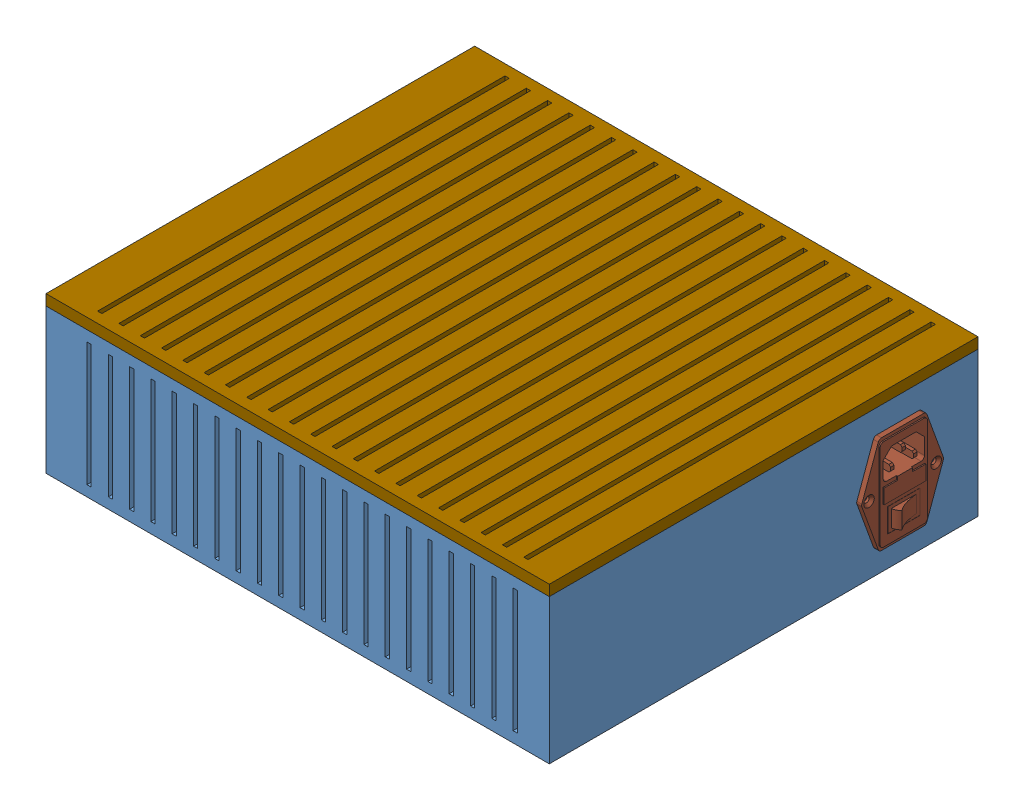
SolidWorks assembly control_box_ssy, configuration Default. Lengths in mm.
Overall size (358.32 92.75 255.52).
319 component instances, 47 part files, 18 mates.
Components (placement in the parent):
- control_box-1: control_box [Default] at (146.6562 115.1986 240.0764) size (300 86.35 255.52)
- PSU-1: PSU [Default] at (123.0062 115.1986 301.4884) x (0 0 -1) z (1 0 0) size (120 65 240)
- Duex5-1: Duex5 [Default] at (64.5062 115.1986 168.6644) size (119.17 14.96 75.22)
  - Duet WiFi v1-1: Duet WiFi v1 [Default] at origin (suppressed, hidden)
  - 2 pole terminal block v7-1: 2 pole terminal block v7 [Default] at (58.1029 1.6572 -18.2256) x (0 0 -1) z (1 0 0) size (7.2 9 6)
  - 2 pole terminal block v7-2: 2 pole terminal block v7 [Default] at (58.1029 1.6572 -10.5256) x (0 0 -1) z (1 0 0) size (7.2 9 6)
  - Molex PCB 4 pin v3_1-1: Molex PCB 4 pin v3_1 [Default] at (18.0541 13.1477 49.9775) x (1 0 0) z (0 1 0) size (10.16 5.79 14.92)
    - BASE9710016-1: BASE9710016 [Default] at (2.54 2.895 -8.22) size (10.16 5.79 11.5)
    - PINO9710016-1: PINO9710016 [Default] at (1.27 3.325 -0.72) size (0.65 0.65 14.2)
    - PINO9710016-2: PINO9710016 [Default] at (3.81 3.325 -0.72) size (0.65 0.65 14.2)
    - PINO9710016-3: PINO9710016 [Default] at (6.35 3.325 -0.72) size (0.65 0.65 14.2)
    - PINO9710016-4: PINO9710016 [Default] at (8.89 3.325 -0.72) size (0.65 0.65 14.2)
  - Molex PCB 4 pin v3_2-1: Molex PCB 4 pin v3_2 [Default] at (-4.9459 13.1477 49.9775) x (1 0 0) z (0 1 0) size (10.16 5.79 14.92)
    - BASE9710016-1: BASE9710016 [Default] at (2.54 2.895 -8.22) size (10.16 5.79 11.5)
    - PINO9710016-1: PINO9710016 [Default] at (1.27 3.325 -0.72) size (0.65 0.65 14.2)
    - PINO9710016-2: PINO9710016 [Default] at (3.81 3.325 -0.72) size (0.65 0.65 14.2)
    - PINO9710016-3: PINO9710016 [Default] at (6.35 3.325 -0.72) size (0.65 0.65 14.2)
    - PINO9710016-4: PINO9710016 [Default] at (8.89 3.325 -0.72) size (0.65 0.65 14.2)
  - Molex PCB 4 pin v3_3-1: Molex PCB 4 pin v3_3 [Default] at (-27.9459 13.1477 49.9775) x (1 0 0) z (0 1 0) size (10.16 5.79 14.92)
    - BASE9710016-1: BASE9710016 [Default] at (2.54 2.895 -8.22) size (10.16 5.79 11.5)
    - PINO9710016-1: PINO9710016 [Default] at (1.27 3.325 -0.72) size (0.65 0.65 14.2)
    - PINO9710016-2: PINO9710016 [Default] at (3.81 3.325 -0.72) size (0.65 0.65 14.2)
    - PINO9710016-3: PINO9710016 [Default] at (6.35 3.325 -0.72) size (0.65 0.65 14.2)
    - PINO9710016-4: PINO9710016 [Default] at (8.89 3.325 -0.72) size (0.65 0.65 14.2)
  - Molex PCB 4 pin v3_4-1: Molex PCB 4 pin v3_4 [Default] at (-50.9459 13.1477 49.9775) x (1 0 0) z (0 1 0) size (10.16 5.79 14.92)
    - BASE9710016-1: BASE9710016 [Default] at (2.54 2.895 -8.22) size (10.16 5.79 11.5)
    - PINO9710016-1: PINO9710016 [Default] at (1.27 3.325 -0.72) size (0.65 0.65 14.2)
    - PINO9710016-2: PINO9710016 [Default] at (3.81 3.325 -0.72) size (0.65 0.65 14.2)
    - PINO9710016-3: PINO9710016 [Default] at (6.35 3.325 -0.72) size (0.65 0.65 14.2)
    - PINO9710016-4: PINO9710016 [Default] at (8.89 3.325 -0.72) size (0.65 0.65 14.2)
  - 2 pole terminal block v7-3: 2 pole terminal block v7 [Default] at (58.1029 1.6572 -2.8256) x (0 0 -1) z (1 0 0) size (7.2 9 6)
  - Trinamic 2660-PA v3_4-1: Trinamic 2660-PA v3_4 [Default] at (-45.9607 1.6002 32.1353) x (-1 0 -0.000001) z (0.000001 0 -1) size (12 1.6 12)
    - Component1 (5)-1: Component1 (5) [Default] at origin size (12 1.6 12)
  - PCB 7mm cap v8_1-1: PCB 7mm cap v8_1 [Default] at (21.8776 1.5787 20.4495) size (7 8 8.14)
    - Component1_3-1: Component1_3 [Default] at origin size (7 8 8.14)
  - PCB 7mm cap v8_2-1: PCB 7mm cap v8_2 [Default] at (-1.1224 1.5787 20.4495) size (7 8 8.14)
    - Component1_3-1: Component1_3 [Default] at origin size (7 8 8.14)
  - PCB 7mm cap v8_3-1: PCB 7mm cap v8_3 [Default] at (-25.1224 1.5787 20.4495) size (7 8 8.14)
    - Component1_3-1: Component1_3 [Default] at origin size (7 8 8.14)
  - PCB 7mm cap v8_4-1: PCB 7mm cap v8_4 [Default] at (-48.1224 1.5787 20.4495) size (7 8 8.14)
    - Component1_3-1: Component1_3 [Default] at origin size (7 8 8.14)
  - Molex PCB 2 pin v2 (6)_1-1: Molex PCB 2 pin v2 (6)_1 [Default] at (-44.2809 13.1082 -19.4574) x (1 0 0) z (0 1 0) size (10.16 5.79 14.92)
    - BASE9710016-1: BASE9710016 [Default] at (2.54 2.895 -8.22) size (10.16 5.79 11.5)
    - PINO9710016-1: PINO9710016 [Default] at (1.27 3.325 -0.72) size (0.65 0.65 14.2)
    - PINO9710016-2: PINO9710016 [Default] at (3.81 3.325 -0.72) size (0.65 0.65 14.2)
  - Molex PCB 2 pin v2 (6)_2-1: Molex PCB 2 pin v2 (6)_2 [Default] at (-37.2809 13.1082 -19.4574) x (1 0 0) z (0 1 0) size (10.16 5.79 14.92)
    - BASE9710016-1: BASE9710016 [Default] at (2.54 2.895 -8.22) size (10.16 5.79 11.5)
    - PINO9710016-1: PINO9710016 [Default] at (1.27 3.325 -0.72) size (0.65 0.65 14.2)
    - PINO9710016-2: PINO9710016 [Default] at (3.81 3.325 -0.72) size (0.65 0.65 14.2)
  - Molex PCB 2 pin v2 (6)_3-1: Molex PCB 2 pin v2 (6)_3 [Default] at (-30.2809 13.1082 -19.4574) x (1 0 0) z (0 1 0) size (10.16 5.79 14.92)
    - BASE9710016-1: BASE9710016 [Default] at (2.54 2.895 -8.22) size (10.16 5.79 11.5)
    - PINO9710016-1: PINO9710016 [Default] at (1.27 3.325 -0.72) size (0.65 0.65 14.2)
    - PINO9710016-2: PINO9710016 [Default] at (3.81 3.325 -0.72) size (0.65 0.65 14.2)
  - Molex PCB 3 pin v2 v6_1-1: Molex PCB 3 pin v2 v6_1 [Default] at (-22.2009 13.1082 -19.4574) x (1 0 0) z (0 1 0) size (7.62 5.79 14.92)
    - BASE9710016_2-1: BASE9710016_2 [Default] at (2.54 2.895 -8.22) size (7.62 5.79 11.5)
    - PINO9710016_2-1: PINO9710016_2 [Default] at (1.27 3.325 -0.72) size (0.65 0.65 14.2)
    - PINO9710016_2-2: PINO9710016_2 [Default] at (3.81 3.325 -0.72) size (0.65 0.65 14.2)
    - PINO9710016_2-3: PINO9710016_2 [Default] at (6.35 3.325 -0.72) size (0.65 0.65 14.2)
  - Molex PCB 3 pin v2 v6_2-1: Molex PCB 3 pin v2 v6_2 [Default] at (-12.2009 13.1082 -19.4574) x (1 0 0) z (0 1 0) size (7.62 5.79 14.92)
    - BASE9710016_2-1: BASE9710016_2 [Default] at (2.54 2.895 -8.22) size (7.62 5.79 11.5)
    - PINO9710016_2-1: PINO9710016_2 [Default] at (1.27 3.325 -0.72) size (0.65 0.65 14.2)
    - PINO9710016_2-2: PINO9710016_2 [Default] at (3.81 3.325 -0.72) size (0.65 0.65 14.2)
    - PINO9710016_2-3: PINO9710016_2 [Default] at (6.35 3.325 -0.72) size (0.65 0.65 14.2)
  - Molex PCB 3 pin v2 v6_3-1: Molex PCB 3 pin v2 v6_3 [Default] at (-2.2009 13.1082 -19.4574) x (1 0 0) z (0 1 0) size (7.62 5.79 14.92)
    - BASE9710016_2-1: BASE9710016_2 [Default] at (2.54 2.895 -8.22) size (7.62 5.79 11.5)
    - PINO9710016_2-1: PINO9710016_2 [Default] at (1.27 3.325 -0.72) size (0.65 0.65 14.2)
    - PINO9710016_2-2: PINO9710016_2 [Default] at (3.81 3.325 -0.72) size (0.65 0.65 14.2)
    - PINO9710016_2-3: PINO9710016_2 [Default] at (6.35 3.325 -0.72) size (0.65 0.65 14.2)
  - Molex PCB 3 pin v2 v6_4-1: Molex PCB 3 pin v2 v6_4 [Default] at (7.7991 13.1082 -19.4574) x (1 0 0) z (0 1 0) size (7.62 5.79 14.92)
    - BASE9710016_2-1: BASE9710016_2 [Default] at (2.54 2.895 -8.22) size (7.62 5.79 11.5)
    - PINO9710016_2-1: PINO9710016_2 [Default] at (1.27 3.325 -0.72) size (0.65 0.65 14.2)
    - PINO9710016_2-2: PINO9710016_2 [Default] at (3.81 3.325 -0.72) size (0.65 0.65 14.2)
    - PINO9710016_2-3: PINO9710016_2 [Default] at (6.35 3.325 -0.72) size (0.65 0.65 14.2)
  - Molex PCB 3 pin v2 v6_5-1: Molex PCB 3 pin v2 v6_5 [Default] at (17.7991 13.1082 -19.4574) x (1 0 0) z (0 1 0) size (7.62 5.79 14.92)
    - BASE9710016_2-1: BASE9710016_2 [Default] at (2.54 2.895 -8.22) size (7.62 5.79 11.5)
    - PINO9710016_2-1: PINO9710016_2 [Default] at (1.27 3.325 -0.72) size (0.65 0.65 14.2)
    - PINO9710016_2-2: PINO9710016_2 [Default] at (3.81 3.325 -0.72) size (0.65 0.65 14.2)
    - PINO9710016_2-3: PINO9710016_2 [Default] at (6.35 3.325 -0.72) size (0.65 0.65 14.2)
  - PCB 7mm cap v8_5-1: PCB 7mm cap v8_5 [Default] at (31.8776 1.5787 0.4495) size (7 8 8.14)
    - Component1_3-1: Component1_3 [Default] at origin size (7 8 8.14)
  - PCB 7mm cap v8_6-1: PCB 7mm cap v8_6 [Default] at (36.8776 1.5787 -19.5505) size (7 8 8.14)
    - Component1_3-1: Component1_3 [Default] at origin size (7 8 8.14)
  - MOSFET v9-1: MOSFET v9 [Default] at (44.8765 1.6199 -9.2021) x (0 0 1) z (-1 0 0) size (6.4 2.4 9.33)
  - MOSFET v9-2: MOSFET v9 [Default] at (23.8765 1.6199 -9.2021) x (0 0 1) z (-1 0 0) size (6.4 2.4 9.33)
  - MOSFET v9-3: MOSFET v9 [Default] at (23.8765 1.6199 9.7979) x (0 0 1) z (-1 0 0) size (6.4 2.4 9.33)
  - MOSFET v9-4: MOSFET v9 [Default] at (44.8765 1.6199 9.7979) x (0 0 1) z (-1 0 0) size (6.4 2.4 9.33)
  - PCB 7mm cap v8_7-1: PCB 7mm cap v8_7 [Default] at (-42.1224 1.5787 6.4495) size (7 8 8.14)
    - Component1_3-1: Component1_3 [Default] at origin size (7 8 8.14)
  - PCB 7mm cap v8_8-1: PCB 7mm cap v8_8 [Default] at (-54.5623 1.5787 -3.6684) size (7 8 8.14)
    - Component1_3-1: Component1_3 [Default] at origin size (7 8 8.14)
  - Micro P v5_1-1: Micro P v5_1 [Default] at (-11.5775 1.6187 -10.0194) x (-1 0 0) z (0 0 -1) size (5 1.2 5.8)
    - Component1 (2)-1: Component1 (2) [Default] at origin size (5 1.2 5.8)
  - Micro P v5_2-1: Micro P v5_2 [Default] at (-19.5775 1.6187 -5.0194) x (-1 0 0) z (0 0 -1) size (5 1.2 5.8)
    - Component1 (2)-1: Component1 (2) [Default] at origin size (5 1.2 5.8)
- Duet WIfi Rev 4-1: Duet WIfi Rev 4 [Default] at (193.5062 115.1986 168.6644) size (129 22.52 100)
  - Main PCB v56-1: Main PCB v56 [Default] at origin size (123 1.6 100)
  - Molex PCB 2 pin v2-1: Molex PCB 2 pin v2 [Default] at (-35.5344 13.1082 -6.1109) x (1 0 0) z (0 1 0) size (5.08 5.79 14.92)
    - BASE9710016_1-1: BASE9710016_1 [Default] at (2.54 2.895 -8.22) size (5.08 5.79 11.5)
    - PINO9710016_1-1: PINO9710016_1 [Default] at (1.27 3.325 -0.72) size (0.65 0.65 14.2)
    - PINO9710016_1-2: PINO9710016_1 [Default] at (3.81 3.325 -0.72) size (0.65 0.65 14.2)
  - Molex PCB 2 pin v2_1-1: Molex PCB 2 pin v2_1 [Default] at (-28.4802 13.1082 -6.1109) x (1 0 0) z (0 1 0) size (5.08 5.79 14.92)
    - BASE9710016_1-1: BASE9710016_1 [Default] at (2.54 2.895 -8.22) size (5.08 5.79 11.5)
    - PINO9710016_1-1: PINO9710016_1 [Default] at (1.27 3.325 -0.72) size (0.65 0.65 14.2)
    - PINO9710016_1-2: PINO9710016_1 [Default] at (3.81 3.325 -0.72) size (0.65 0.65 14.2)
  - microSD1 v4-1: microSD1 v4 [Default] at (-62.4462 1.5952 12.9853) x (0 0 1) z (-1 0 0) size (14.1 1.88 15.2)
  - Molex PCB 2 pin v2_2-1: Molex PCB 2 pin v2_2 [Default] at (13.9179 13.1082 2.5426) x (1 0 0) z (0 1 0) size (5.08 5.79 14.92)
    - BASE9710016_1-1: BASE9710016_1 [Default] at (2.54 2.895 -8.22) size (5.08 5.79 11.5)
    - PINO9710016_1-1: PINO9710016_1 [Default] at (1.27 3.325 -0.72) size (0.65 0.65 14.2)
    - PINO9710016_1-2: PINO9710016_1 [Default] at (3.81 3.325 -0.72) size (0.65 0.65 14.2)
  - Molex PCB 2 pin v2_3-1: Molex PCB 2 pin v2_3 [Default] at (20.2886 13.1082 2.5426) x (1 0 0) z (0 1 0) size (5.08 5.79 14.92)
    - BASE9710016_1-1: BASE9710016_1 [Default] at (2.54 2.895 -8.22) size (5.08 5.79 11.5)
    - PINO9710016_1-1: PINO9710016_1 [Default] at (1.27 3.325 -0.72) size (0.65 0.65 14.2)
    - PINO9710016_1-2: PINO9710016_1 [Default] at (3.81 3.325 -0.72) size (0.65 0.65 14.2)
  - Molex PCB 2 pin v2_4-1: Molex PCB 2 pin v2_4 [Default] at (26.5531 13.1082 2.5426) x (1 0 0) z (0 1 0) size (5.08 5.79 14.92)
    - BASE9710016_1-1: BASE9710016_1 [Default] at (2.54 2.895 -8.22) size (5.08 5.79 11.5)
    - PINO9710016_1-1: PINO9710016_1 [Default] at (1.27 3.325 -0.72) size (0.65 0.65 14.2)
    - PINO9710016_1-2: PINO9710016_1 [Default] at (3.81 3.325 -0.72) size (0.65 0.65 14.2)
  - Molex PCB 2 pin v2_5-1: Molex PCB 2 pin v2_5 [Default] at (33.1361 13.1082 2.5426) x (1 0 0) z (0 1 0) size (5.08 5.79 14.92)
    - BASE9710016_1-1: BASE9710016_1 [Default] at (2.54 2.895 -8.22) size (5.08 5.79 11.5)
    - PINO9710016_1-1: PINO9710016_1 [Default] at (1.27 3.325 -0.72) size (0.65 0.65 14.2)
    - PINO9710016_1-2: PINO9710016_1 [Default] at (3.81 3.325 -0.72) size (0.65 0.65 14.2)
  - Molex PCB 2 pin v2_6-1: Molex PCB 2 pin v2_6 [Default] at (39.7191 13.1082 2.5426) x (1 0 0) z (0 1 0) size (5.08 5.79 14.92)
    - BASE9710016_1-1: BASE9710016_1 [Default] at (2.54 2.895 -8.22) size (5.08 5.79 11.5)
    - PINO9710016_1-1: PINO9710016_1 [Default] at (1.27 3.325 -0.72) size (0.65 0.65 14.2)
    - PINO9710016_1-2: PINO9710016_1 [Default] at (3.81 3.325 -0.72) size (0.65 0.65 14.2)
  - Molex PCB 3 pin v2 v6-1: Molex PCB 3 pin v2 v6 [Default] at (-20.7566 13.2093 -6.0914) x (1 0 0) z (0 1 0) size (7.62 5.79 14.92)
    - BASE9710016_2-1: BASE9710016_2 [Default] at (2.54 2.895 -8.22) size (7.62 5.79 11.5)
    - PINO9710016_2-1: PINO9710016_2 [Default] at (1.27 3.325 -0.72) size (0.65 0.65 14.2)
    - PINO9710016_2-2: PINO9710016_2 [Default] at (3.81 3.325 -0.72) size (0.65 0.65 14.2)
    - PINO9710016_2-3: PINO9710016_2 [Default] at (6.35 3.325 -0.72) size (0.65 0.65 14.2)
  - Molex PCB 3 pin v2 v6_1-1: Molex PCB 3 pin v2 v6_1 [Default] at (-10.5889 13.2093 -6.0914) x (1 0 0) z (0 1 0) size (7.62 5.79 14.92)
    - BASE9710016_2-1: BASE9710016_2 [Default] at (2.54 2.895 -8.22) size (7.62 5.79 11.5)
    - PINO9710016_2-1: PINO9710016_2 [Default] at (1.27 3.325 -0.72) size (0.65 0.65 14.2)
    - PINO9710016_2-2: PINO9710016_2 [Default] at (3.81 3.325 -0.72) size (0.65 0.65 14.2)
    - PINO9710016_2-3: PINO9710016_2 [Default] at (6.35 3.325 -0.72) size (0.65 0.65 14.2)
  - Molex PCB 3 pin v2 v6_2-1: Molex PCB 3 pin v2 v6_2 [Default] at (-1.0164 13.2093 -6.0914) x (1 0 0) z (0 1 0) size (7.62 5.79 14.92)
    - BASE9710016_2-1: BASE9710016_2 [Default] at (2.54 2.895 -8.22) size (7.62 5.79 11.5)
    - PINO9710016_2-1: PINO9710016_2 [Default] at (1.27 3.325 -0.72) size (0.65 0.65 14.2)
    - PINO9710016_2-2: PINO9710016_2 [Default] at (3.81 3.325 -0.72) size (0.65 0.65 14.2)
    - PINO9710016_2-3: PINO9710016_2 [Default] at (6.35 3.325 -0.72) size (0.65 0.65 14.2)
  - Molex PCB 3 pin v2 v6_3-1: Molex PCB 3 pin v2 v6_3 [Default] at (9.3326 13.2093 -6.0914) x (1 0 0) z (0 1 0) size (7.62 5.79 14.92)
    - BASE9710016_2-1: BASE9710016_2 [Default] at (2.54 2.895 -8.22) size (7.62 5.79 11.5)
    - PINO9710016_2-1: PINO9710016_2 [Default] at (1.27 3.325 -0.72) size (0.65 0.65 14.2)
    - PINO9710016_2-2: PINO9710016_2 [Default] at (3.81 3.325 -0.72) size (0.65 0.65 14.2)
    - PINO9710016_2-3: PINO9710016_2 [Default] at (6.35 3.325 -0.72) size (0.65 0.65 14.2)
  - Molex PCB 3 pin v2 v6_4-1: Molex PCB 3 pin v2 v6_4 [Default] at (19.2437 13.2093 -6.0914) x (1 0 0) z (0 1 0) size (7.62 5.79 14.92)
    - BASE9710016_2-1: BASE9710016_2 [Default] at (2.54 2.895 -8.22) size (7.62 5.79 11.5)
    - PINO9710016_2-1: PINO9710016_2 [Default] at (1.27 3.325 -0.72) size (0.65 0.65 14.2)
    - PINO9710016_2-2: PINO9710016_2 [Default] at (3.81 3.325 -0.72) size (0.65 0.65 14.2)
    - PINO9710016_2-3: PINO9710016_2 [Default] at (6.35 3.325 -0.72) size (0.65 0.65 14.2)
  - Molex PCB 4 pin v3-1: Molex PCB 4 pin v3 [Default] at (-37.9459 13.1477 49.9775) x (1 0 0) z (0 1 0) size (10.16 5.79 14.92)
    - BASE9710016-1: BASE9710016 [Default] at (2.54 2.895 -8.22) size (10.16 5.79 11.5)
    - PINO9710016-1: PINO9710016 [Default] at (1.27 3.325 -0.72) size (0.65 0.65 14.2)
    - PINO9710016-2: PINO9710016 [Default] at (3.81 3.325 -0.72) size (0.65 0.65 14.2)
    - PINO9710016-3: PINO9710016 [Default] at (6.35 3.325 -0.72) size (0.65 0.65 14.2)
    - PINO9710016-4: PINO9710016 [Default] at (8.89 3.325 -0.72) size (0.65 0.65 14.2)
  - Molex PCB 4 pin v3_1-1: Molex PCB 4 pin v3_1 [Default] at (-26.9715 13.1477 49.9775) x (1 0 0) z (0 1 0) size (10.16 5.79 14.92)
    - BASE9710016-1: BASE9710016 [Default] at (2.54 2.895 -8.22) size (10.16 5.79 11.5)
    - PINO9710016-1: PINO9710016 [Default] at (1.27 3.325 -0.72) size (0.65 0.65 14.2)
    - PINO9710016-2: PINO9710016 [Default] at (3.81 3.325 -0.72) size (0.65 0.65 14.2)
    - PINO9710016-3: PINO9710016 [Default] at (6.35 3.325 -0.72) size (0.65 0.65 14.2)
    - PINO9710016-4: PINO9710016 [Default] at (8.89 3.325 -0.72) size (0.65 0.65 14.2)
  - Molex PCB 4 pin v3_2-1: Molex PCB 4 pin v3_2 [Default] at (-13.0474 13.1477 -49.9787) x (-1 0 0) z (0 1 0) size (10.16 5.79 14.92)
    - BASE9710016-1: BASE9710016 [Default] at (2.54 2.895 -8.22) size (10.16 5.79 11.5)
    - PINO9710016-1: PINO9710016 [Default] at (1.27 3.325 -0.72) size (0.65 0.65 14.2)
    - PINO9710016-2: PINO9710016 [Default] at (3.81 3.325 -0.72) size (0.65 0.65 14.2)
    - PINO9710016-3: PINO9710016 [Default] at (6.35 3.325 -0.72) size (0.65 0.65 14.2)
    - PINO9710016-4: PINO9710016 [Default] at (8.89 3.325 -0.72) size (0.65 0.65 14.2)
  - Molex PCB 4 pin v3_3-1: Molex PCB 4 pin v3_3 [Default] at (3.87 13.1477 -49.9787) x (-1 0 0) z (0 1 0) size (10.16 5.79 14.92)
    - BASE9710016-1: BASE9710016 [Default] at (2.54 2.895 -8.22) size (10.16 5.79 11.5)
    - PINO9710016-1: PINO9710016 [Default] at (1.27 3.325 -0.72) size (0.65 0.65 14.2)
    - PINO9710016-2: PINO9710016 [Default] at (3.81 3.325 -0.72) size (0.65 0.65 14.2)
    - PINO9710016-3: PINO9710016 [Default] at (6.35 3.325 -0.72) size (0.65 0.65 14.2)
    - PINO9710016-4: PINO9710016 [Default] at (8.89 3.325 -0.72) size (0.65 0.65 14.2)
  - Molex PCB 4 pin v3_4-1: Molex PCB 4 pin v3_4 [Default] at (20.2963 13.1477 -49.9787) x (-1 0 0) z (0 1 0) size (10.16 5.79 14.92)
    - BASE9710016-1: BASE9710016 [Default] at (2.54 2.895 -8.22) size (10.16 5.79 11.5)
    - PINO9710016-1: PINO9710016 [Default] at (1.27 3.325 -0.72) size (0.65 0.65 14.2)
    - PINO9710016-2: PINO9710016 [Default] at (3.81 3.325 -0.72) size (0.65 0.65 14.2)
    - PINO9710016-3: PINO9710016 [Default] at (6.35 3.325 -0.72) size (0.65 0.65 14.2)
    - PINO9710016-4: PINO9710016 [Default] at (8.89 3.325 -0.72) size (0.65 0.65 14.2)
  - Molex PCB 4 pin v3_5-1: Molex PCB 4 pin v3_5 [Default] at (36.6134 13.1477 -49.9787) x (-1 0 0) z (0 1 0) size (10.16 5.79 14.92)
    - BASE9710016-1: BASE9710016 [Default] at (2.54 2.895 -8.22) size (10.16 5.79 11.5)
    - PINO9710016-1: PINO9710016 [Default] at (1.27 3.325 -0.72) size (0.65 0.65 14.2)
    - PINO9710016-2: PINO9710016 [Default] at (3.81 3.325 -0.72) size (0.65 0.65 14.2)
    - PINO9710016-3: PINO9710016 [Default] at (6.35 3.325 -0.72) size (0.65 0.65 14.2)
    - PINO9710016-4: PINO9710016 [Default] at (8.89 3.325 -0.72) size (0.65 0.65 14.2)
  - Molex PCB 4 pin v3_6-1: Molex PCB 4 pin v3_6 [Default] at (53.5582 13.1477 -49.9787) x (-1 0 0) z (0 1 0) size (10.16 5.79 14.92)
    - BASE9710016-1: BASE9710016 [Default] at (2.54 2.895 -8.22) size (10.16 5.79 11.5)
    - PINO9710016-1: PINO9710016 [Default] at (1.27 3.325 -0.72) size (0.65 0.65 14.2)
    - PINO9710016-2: PINO9710016 [Default] at (3.81 3.325 -0.72) size (0.65 0.65 14.2)
    - PINO9710016-3: PINO9710016 [Default] at (6.35 3.325 -0.72) size (0.65 0.65 14.2)
    - PINO9710016-4: PINO9710016 [Default] at (8.89 3.325 -0.72) size (0.65 0.65 14.2)
  - Molex PCB 4 pin v3_7-1: Molex PCB 4 pin v3_7 [Default] at (53.5582 13.1477 -42.9934) x (-1 0 0) z (0 1 0) size (10.16 5.79 14.92)
    - BASE9710016-1: BASE9710016 [Default] at (2.54 2.895 -8.22) size (10.16 5.79 11.5)
    - PINO9710016-1: PINO9710016 [Default] at (1.27 3.325 -0.72) size (0.65 0.65 14.2)
    - PINO9710016-2: PINO9710016 [Default] at (3.81 3.325 -0.72) size (0.65 0.65 14.2)
    - PINO9710016-3: PINO9710016 [Default] at (6.35 3.325 -0.72) size (0.65 0.65 14.2)
    - PINO9710016-4: PINO9710016 [Default] at (8.89 3.325 -0.72) size (0.65 0.65 14.2)
  - 2 pole terminal block v7-1: 2 pole terminal block v7 [Default] at (-27.4689 1.6269 -46.8568) x (-1 0 0) z (0 0 -1) size (7.2 9 6)
  - 2 pole terminal block v7-2: 2 pole terminal block v7 [Default] at (-35.1283 1.6572 -46.8568) x (-1 0 0) z (0 0 -1) size (7.2 9 6)
  - 2 pole terminal block large v7-1: 2 pole terminal block large v7 [Default] at (55.6089 1.6 -4.9109) x (0 0 -1) z (1 0 0) size (13.4 19.1 11)
  - 2 pole terminal block large v7-2: 2 pole terminal block large v7 [Default] at (55.6089 1.6 27.2029) x (0 0 -1) z (1 0 0) size (13.4 19.1 11)
  - Molex PCB 2 pin v2_7-1: Molex PCB 2 pin v2_7 [Default] at (61.0807 13.1082 40.8944) x (0 0 -1) z (0 1 0) size (5.08 5.79 14.92)
    - BASE9710016_1-1: BASE9710016_1 [Default] at (2.54 2.895 -8.22) size (5.08 5.79 11.5)
    - PINO9710016_1-1: PINO9710016_1 [Default] at (1.27 3.325 -0.72) size (0.65 0.65 14.2)
    - PINO9710016_1-2: PINO9710016_1 [Default] at (3.81 3.325 -0.72) size (0.65 0.65 14.2)
  - Molex PCB 3 pin v2 v6_5-1: Molex PCB 3 pin v2 v6_5 [Default] at (61.3453 13.2093 -15.0112) x (0 0 -1) z (0 1 0) size (7.62 5.79 14.92)
    - BASE9710016_2-1: BASE9710016_2 [Default] at (2.54 2.895 -8.22) size (7.62 5.79 11.5)
    - PINO9710016_2-1: PINO9710016_2 [Default] at (1.27 3.325 -0.72) size (0.65 0.65 14.2)
    - PINO9710016_2-2: PINO9710016_2 [Default] at (3.81 3.325 -0.72) size (0.65 0.65 14.2)
    - PINO9710016_2-3: PINO9710016_2 [Default] at (6.35 3.325 -0.72) size (0.65 0.65 14.2)
  - Pin Header 2x5 TH Pitch 2.54mm v4-1: Pin Header 2x5 TH Pitch 2.54mm v4 [Default] at (-5.2178 1.6022 33.3605) x (1 0 0) z (0 1 0) size (12.7 5.08 12.7)
    - Component1_5-1: Component1_5 [Default] at origin size (0.63 0.63 12.7)
    - Component2-1: Component2 [Default] at origin size (0.63 0.63 12.7)
    - Component3-1: Component3 [Default] at origin size (0.63 0.63 12.7)
    - Component4-1: Component4 [Default] at origin size (0.63 0.63 12.7)
    - Component5-1: Component5 [Default] at origin size (0.63 0.63 12.7)
    - Component6-1: Component6 [Default] at origin size (2.54 5.08 2.8)
    - Component7-1: Component7 [Default] at origin size (0.63 0.63 12.7)
    - Component8-1: Component8 [Default] at origin size (2.54 5.08 2.8)
    - Component9-1: Component9 [Default] at origin size (2.54 5.08 2.8)
    - Component10-1: Component10 [Default] at origin size (0.63 0.63 12.7)
    - Component11-1: Component11 [Default] at origin size (0.63 0.63 12.7)
    - Component12-1: Component12 [Default] at origin size (2.54 5.08 2.8)
    - Component13-1: Component13 [Default] at origin size (2.54 5.08 2.8)
    - Component14-1: Component14 [Default] at origin size (0.63 0.63 12.7)
    - Component15-1: Component15 [Default] at origin size (0.63 0.63 12.7)
  - Arm cortex Sam4E8E v6 v7-1: Arm cortex Sam4E8E v6 v7 [Default] at (-17.0062 1.6459 20.877) x (0.707107 0 0.707107) z (-0.707107 0 0.707107) size (22 1.6 22)
    - Component1-1: Component1 [Default] at origin size (22 1.6 22)
  - Trinamic 2660-PA v3-1: Trinamic 2660-PA v3 [Default] at (-26.4607 1.6002 -30.8647) x (-1 0 -0.000001) z (0.000001 0 -1) size (12 1.6 12)
    - Component1_1-1: Component1_1 [Default] at origin size (12 1.6 12)
  - Trinamic 2660-PA v3-2: Trinamic 2660-PA v3 [Default] at (-7.8607 1.6002 -30.8647) x (-1 0 -0.000001) z (0.000001 0 -1) size (12 1.6 12)
    - Component1_1-1: Component1_1 [Default] at origin size (12 1.6 12)
  - Trinamic 2660-PA v3-3: Trinamic 2660-PA v3 [Default] at (10.5393 1.6002 -30.8647) x (-1 0 -0.000001) z (0.000001 0 -1) size (12 1.6 12)
    - Component1_1-1: Component1_1 [Default] at origin size (12 1.6 12)
  - Trinamic 2660-PA v3-4: Trinamic 2660-PA v3 [Default] at (28.8037 1.6002 -30.8647) x (-1 0 -0.000001) z (0.000001 0 -1) size (12 1.6 12)
    - Component1_1-1: Component1_1 [Default] at origin size (12 1.6 12)
  - Trinamic 2660-PA v3_1-1: Trinamic 2660-PA v3_1 [Default] at (48.089 1.6002 -27.9115) x (-1 0 -0.000001) z (0.000001 0 -1) size (12 1.6 12)
    - Component1_1-1: Component1_1 [Default] at origin size (12 1.6 12)
  - MOSFET v9-1: MOSFET v9 [Default] at (-45.1235 1.6199 -39.2021) x (0 0 1) z (-1 0 0) size (6.4 2.4 9.33)
  - MOSFET v9-2: MOSFET v9 [Default] at (-45.3181 1.6199 -21.674) x (-1 0 0) z (0 0 -1) size (6.4 2.4 9.33)
  - Power reg v5-1: Power reg v5 [Default] at (54.1912 1.6402 16.2036) x (-1 0 0) z (0 0 -1) size (6.8 2.8 9.2)
  - Duet Wifi daughter board  v25-1: Duet Wifi daughter board  v25 [Default] at (-55.2292 8.9057 28.17) size (25 1.6 18.4)
    - Component1_2-1: Component1_2 [Default] at (-0.2708 -7.3057 3.83) size (25 1.6 18.4)
  - PCB 7mm cap v8-1: PCB 7mm cap v8 [Default] at (-5.0295 1.5787 -16.3984) size (7 8 8.14)
    - Component1_3-1: Component1_3 [Default] at origin size (7 8 8.14)
  - PCB 7mm cap v8_1-1: PCB 7mm cap v8_1 [Default] at (-27.7717 1.5787 -16.5362) size (7 8 8.14)
    - Component1_3-1: Component1_3 [Default] at origin size (7 8 8.14)
  - PCB 7mm cap v8_2-1: PCB 7mm cap v8_2 [Default] at (13.3988 1.5787 -16.4775) size (7 8 8.14)
    - Component1_3-1: Component1_3 [Default] at origin size (7 8 8.14)
  - PCB 7mm cap v8_3-1: PCB 7mm cap v8_3 [Default] at (29.911 1.5787 -16.3984) size (7 8 8.14)
    - Component1_3-1: Component1_3 [Default] at origin size (7 8 8.14)
  - PCB 7mm cap v8_4-1: PCB 7mm cap v8_4 [Default] at (49.8005 1.5787 -16.1299) x (-0.000012 0 -1) z (1 0 -0.000012) size (7 8 8.14)
    - Component1_3-1: Component1_3 [Default] at origin size (7 8 8.14)
  - PCB 7mm cap v8_5-1: PCB 7mm cap v8_5 [Default] at (42.4342 1.5787 14.6374) x (0 0 1) z (-1 0 0) size (7 8 8.14)
    - Component1_3-1: Component1_3 [Default] at origin size (7 8 8.14)
  - PCB 7mm cap v8_6-1: PCB 7mm cap v8_6 [Default] at (56.2359 1.5787 5.2974) size (7 8 8.14)
    - Component1_3-1: Component1_3 [Default] at origin size (7 8 8.14)
  - PCB 7mm cap v8_7-1: PCB 7mm cap v8_7 [Default] at (37.0801 1.5787 25.7026) x (0 0 -1) z (1 0 0) size (7 8 8.14)
    - Component1_3-1: Component1_3 [Default] at origin size (7 8 8.14)
  - PCB 7mm cap v8_8-1: PCB 7mm cap v8_8 [Default] at (16.7939 1.5787 25.7621) x (-1 0 0) z (0 0 -1) size (7 8 8.14)
    - Component1_3-1: Component1_3 [Default] at origin size (7 8 8.14)
  - PCB 7mm cap v8_9-1: PCB 7mm cap v8_9 [Default] at (-51.4074 1.5787 -31.2726) x (-1 0 0) z (0 0 -1) size (7 8 8.14)
    - Component1_3-1: Component1_3 [Default] at origin size (7 8 8.14)
  - Power reg R2 v4-1: Power reg R2 v4 [Default] at (15.3184 1.6131 15.7902) size (6.8 2 7)
  - Micro P v5-1: Micro P v5 [Default] at (6.2858 1.6187 3.3147) size (5 1.2 5.8)
    - Component1_4-1: Component1_4 [Default] at origin size (5 1.2 5.8)
  - Micro P v5-2: Micro P v5 [Default] at (-46.5775 1.6187 45.9806) x (0 0 -1) z (1 0 0) size (5 1.2 5.8)
    - Component1_4-1: Component1_4 [Default] at origin size (5 1.2 5.8)
  - Micro P v5-3: Micro P v5 [Default] at (-45.3709 1.6187 -11.358) x (0 0 -1) z (1 0 0) size (5 1.2 5.8)
    - Component1_4-1: Component1_4 [Default] at origin size (5 1.2 5.8)
  - choke v6-1: choke v6 [Default] at (24.2066 1.6283 19.4931) size (5.4 2.7 5.4)
  - button switch v9-1: button switch v9 [Default] at (-59.392 1.6111 -12.4706) size (5 2 6.4)
  - button switch v9-2: button switch v9 [Default] at (-59.362 1.6111 -20.1424) size (5 2 6.4)
  - Pin Header 2x5 TH Pitch 2.54mm v4_1-1: Pin Header 2x5 TH Pitch 2.54mm v4_1 [Default] at (18.7961 1.6 37.7617) x (1 0 0) z (0 1 0) size (12.7 5.08 12.7)
    - Component1_5-1: Component1_5 [Default] at origin size (0.63 0.63 12.7)
    - Component2-1: Component2 [Default] at origin size (0.63 0.63 12.7)
    - Component3-1: Component3 [Default] at origin size (0.63 0.63 12.7)
    - Component4-1: Component4 [Default] at origin size (0.63 0.63 12.7)
    - Component5-1: Component5 [Default] at origin size (0.63 0.63 12.7)
    - Component6-1: Component6 [Default] at origin size (2.54 5.08 2.8)
    - Component7-1: Component7 [Default] at origin size (0.63 0.63 12.7)
    - Component8-1: Component8 [Default] at origin size (2.54 5.08 2.8)
    - Component9-1: Component9 [Default] at origin size (2.54 5.08 2.8)
    - Component10-1: Component10 [Default] at origin size (0.63 0.63 12.7)
    - Component11-1: Component11 [Default] at origin size (0.63 0.63 12.7)
    - Component12-1: Component12 [Default] at origin size (2.54 5.08 2.8)
    - Component13-1: Component13 [Default] at origin size (2.54 5.08 2.8)
    - Component14-1: Component14 [Default] at origin size (0.63 0.63 12.7)
    - Component15-1: Component15 [Default] at origin size (0.63 0.63 12.7)
  - Pin Header 2x5 TH Pitch 2.54mm v4_2-1: Pin Header 2x5 TH Pitch 2.54mm v4_2 [Default] at (38.8572 1.6 37.7617) x (1 0 0) z (0 1 0) size (12.7 5.08 12.7)
    - Component1_5-1: Component1_5 [Default] at origin size (0.63 0.63 12.7)
    - Component2-1: Component2 [Default] at origin size (0.63 0.63 12.7)
    - Component3-1: Component3 [Default] at origin size (0.63 0.63 12.7)
    - Component4-1: Component4 [Default] at origin size (0.63 0.63 12.7)
    - Component5-1: Component5 [Default] at origin size (0.63 0.63 12.7)
    - Component6-1: Component6 [Default] at origin size (2.54 5.08 2.8)
    - Component7-1: Component7 [Default] at origin size (0.63 0.63 12.7)
    - Component8-1: Component8 [Default] at origin size (2.54 5.08 2.8)
    - Component9-1: Component9 [Default] at origin size (2.54 5.08 2.8)
    - Component10-1: Component10 [Default] at origin size (0.63 0.63 12.7)
    - Component11-1: Component11 [Default] at origin size (0.63 0.63 12.7)
    - Component12-1: Component12 [Default] at origin size (2.54 5.08 2.8)
    - Component13-1: Component13 [Default] at origin size (2.54 5.08 2.8)
    - Component14-1: Component14 [Default] at origin size (0.63 0.63 12.7)
    - Component15-1: Component15 [Default] at origin size (0.63 0.63 12.7)
  - 2X5Pin case v6-1: 2X5Pin case v6 [Default] at (17.4643 1.6 37.7689) x (1 0 0) z (0 1 0) size (17.5 7.08 9.6)
    - Component1_6-1: Component1_6 [Default] at origin size (17.5 7.08 9.6)
  - 2X5Pin case v6_1-1: 2X5Pin case v6_1 [Default] at (37.4629 1.6 37.7689) x (1 0 0) z (0 1 0) size (17.5 7.08 9.6)
    - Component1_6-1: Component1_6 [Default] at origin size (17.5 7.08 9.6)
  - 25 pin with case v2-1: 25 pin with case v2 [Default] at (-12.4721 1.5997 44.5087) size (68.5 12.8 7.08)
    - Pin Header 2x15 TH Pitch 2.54mm v2-1: Pin Header 2x15 TH Pitch 2.54mm v2 [Default] at (0 0.0647 1.8778) x (1 0 0) z (0 1 0) size (38.1 5.08 12.7)
    - Pin Header 2x10 TH Pitch 2.54mm v2-1: Pin Header 2x10 TH Pitch 2.54mm v2 [Default] at (38.1 0.0647 1.8778) x (1 0 0) z (0 1 0) size (25.4 5.08 12.7)
    - 2X25Pin case v7-1: 2X25Pin case v7 [Default] x (1 0 0) z (0 1 0) size (68.5 7.08 9.6)
      - Component1_7-1: Component1_7 [Default] at (-1.5 -1.8778 0.0661) size (68.5 7.08 9.6)
  - wifi chip v3-1: wifi chip v3 [Default] at (-52.469 3.2167 31.4135) x (1 0 0) z (0 1 0) size (15 12 2)
- control_box_lid-1: control_box_lid [Default] at (146.6562 195.1986 240.0744) x (0 0 -1) z (1 0 0) size (255.52 12.75 300)
- Screen display unit-1: Screen display unit [Default] at (-27.4738 108.8486 213.9144) x (0 0 1) z (-1 0 0) size (101.6 55.84 49.53)
- C14_passthrough-1: C14_passthrough [Default] at (296.6562 152.0236 160.1982) x (0 0 1) z (-1 0 0) size (48.85 58.2 35.29)
Mates (geometry in assembly coordinates):
- Coincident10: coincident anti-aligned: plane of control_box-1 through (3.0062 195.1986 361.4884) normal (1 0 0); plane of PSU-1 through (3.0062 180.1986 361.4884) normal (-1 0 0)
- Coincident11: coincident anti-aligned: plane of control_box-1 through (290.3062 195.1986 361.4884) normal (0 0 -1); plane of PSU-1 through (243.0062 180.1986 361.4884) normal (0 0 1)
- Coincident12: coincident anti-aligned: plane of control_box-1 through (146.6562 115.1986 240.0764) normal (0 1 0); plane of PSU-1 through (123.0062 115.1986 301.4884) normal (0 -1 0)
- Coincident13: coincident anti-aligned: plane of control_box-1 through (146.6562 115.1986 240.0764) normal (0 1 0); plane of Duex5-1/Duet WiFi v1-1/Duet WiFi v1-1 through (64.5062 115.1986 168.6644) normal (0 -1 0)
- Coincident14: coincident anti-aligned: plane of control_box-1 through (146.6562 115.1986 240.0764) normal (0 1 0); plane of Duet WIfi Rev 4-1/Main PCB v56-1 through (193.5062 115.1986 168.6644) normal (0 -1 0)
- Coincident15: coincident anti-aligned: plane of control_box-1 through (3.0062 195.1986 361.4884) normal (1 0 0); plane of Duex5-1/Duet WiFi v1-1/Duet WiFi v1-1 through (3.0062 115.1986 118.6644) normal (-1 0 0)
- Coincident16: coincident anti-aligned: plane of control_box-1 through (290.3062 195.1986 118.6644) normal (0 0 1); plane of Duex5-1/Duet WiFi v1-1/Duet WiFi v1-1 through (126.0062 115.1986 118.6644) normal (0 0 -1)
- Coincident17: coincident anti-aligned: plane of control_box-1 through (290.3062 195.1986 118.6644) normal (0 0 1); plane of Duet WIfi Rev 4-1/Main PCB v56-1 through (255.0062 115.1986 118.6644) normal (0 0 -1)
- Coincident19: coincident anti-aligned: plane of Duex5-1/Duet WiFi v1-1/Duet WiFi v1-1 through (126.0062 115.1986 218.6644) normal (1 0 0); plane of Duet WIfi Rev 4-1/Duet Wifi daughter board  v25-1/Component1_2-1 through (126.0062 116.7986 192.6644) normal (-1 0 0)
- Coincident26: coincident anti-aligned: plane of control_box-1 through (-3.3438 195.1986 367.8384) normal (-1 0 0); plane of Screen display unit-1 through (-3.3438 108.8486 213.9144) normal (1 0 0)
- Coincident27: coincident aligned: plane of control_box-1 through (146.6562 108.8486 240.0764) normal (0 -1 0); plane of Screen display unit-1 through (-3.3438 108.8486 213.9144) normal (0 -1 0)
- Coincident28: coincident aligned: plane of control_box-1 through (296.6562 195.1986 112.3144) normal (0 0 -1); plane of Screen display unit-1 through (-3.3438 108.8486 112.3144) normal (0 0 -1)
- Coincident29: coincident anti-aligned: plane of control_box-1 through (296.6562 195.1986 367.8384) normal (1 0 0); plane of C14_passthrough-1 through (296.6562 152.0236 160.1982) normal (-1 0 0)
- Coincident30: coincident anti-aligned: plane of control_box-1 through (235.8711 175.6486 146.6832) normal (0 -1 0); plane of C14_passthrough-1 through (280.1562 175.6486 151.6832) normal (0 1 0)
- Coincident31: coincident anti-aligned: line of control_box-1 through (296.6562 128.3986 146.6832) axis (0 1 0); line of C14_passthrough-1 through (296.6562 162.5486 146.6832) axis (0 -1 0)
- Coincident32: coincident anti-aligned: plane of control_box-1 through (146.6562 195.1986 240.0764) normal (0 1 0); plane of control_box_lid-1 through (146.6562 195.1986 240.0744) normal (0 -1 0)
- Coincident33: coincident anti-aligned: plane of control_box-1 through (3.0062 195.1986 361.4884) normal (1 0 0); plane of control_box_lid-1 through (3.0062 188.8486 240.0744) normal (-1 0 0)
- Coincident34: coincident anti-aligned: plane of control_box-1 through (290.3062 195.1986 118.6644) normal (0 0 1); plane of control_box_lid-1 through (146.6562 188.8486 118.6644) normal (0 0 -1)
